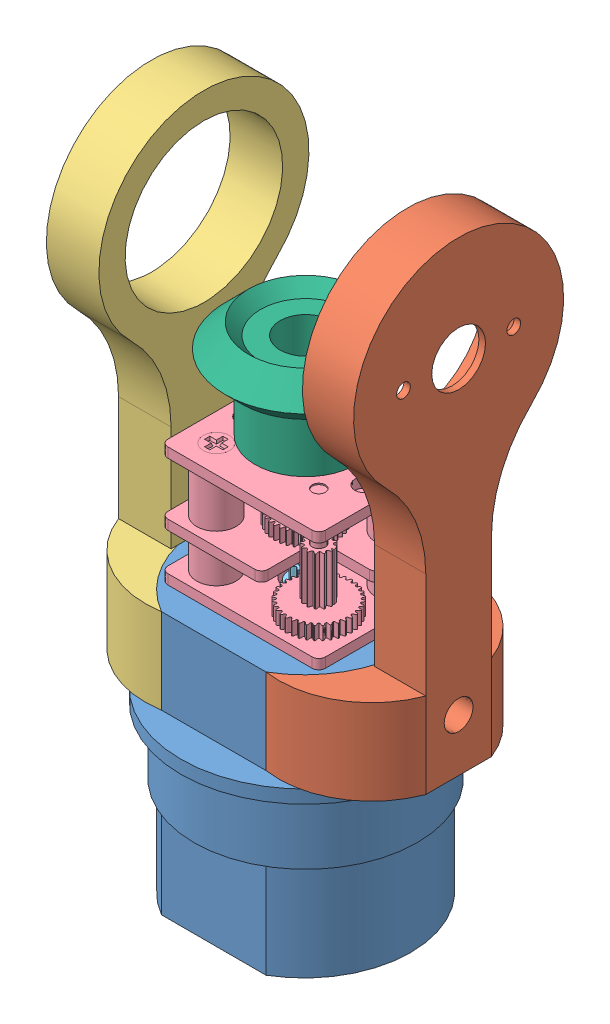
SolidWorks assembly thumb motor module, configuration Default. Lengths in mm.
Overall size (23.4 53 19).
7 component instances, 6 part files, 14 mates.
Components (placement in the parent):
- motor mount v2 thumb-1: motor mount v2 thumb [Default] at origin size (19 24 19)
- outer v2 thumb-1: outer v2 thumb [Default] at (11.65 41 0) x (0 0 1) z (-1 0 0) size (16 35.5 7.67)
- outer gearside v2 thumb-1: outer gearside v2 thumb [Default] at (-11.75 41 0) x (0 0 -1) z (0 -1 0) size (16 7.77 35.5)
- MicroGearMotor v3 Higher Detail Gears No Lead Screw-1: MicroGearMotor v3 Higher Detail Gears No Lead Screw [Default] at (0 20 0) size (12 26.96 10)
  - GearboxScaffolding-1: GearboxScaffolding [Default] at origin size (12 11.35 10)
  - DC Motor-1: DC Motor [Default] at origin size (12 18.75 10)
- rapid 50-8929-1: rapid 50-8929 [Default] at (0 30.11 0) x (0.99917 0 -0.040738) z (0.040738 0 0.99917) size (12.2 7.5 12.2)
Mates (geometry in assembly coordinates):
- Coincident1: coincident aligned: plane of motor mount v2 thumb-1 through (0 0 0) normal (0 1 0); plane of assembly through (0 0 0) normal (0 1 0)
- Coincident2: coincident aligned: plane of motor mount v2 thumb-1 through (0 0 0) normal (1 0 0); plane of assembly through (0 0 0) normal (1 0 0)
- Coincident3: coincident aligned: plane of motor mount v2 thumb-1 through (0 0 0) normal (0 0 1); plane of assembly through (0 0 0) normal (0 0 1)
- Concentric1: concentric aligned: cylinder of motor mount v2 thumb-1 through (-9.5 17.5 0) axis (1 0 0) radius 0.8; cylinder of outer v2 thumb-1 through (7.75 17.5 0) axis (1 0 0) radius 1.1
- Coincident4: coincident anti-aligned: plane of motor mount v2 thumb-1 through (0 13.5 0) normal (0 1 0); plane of outer v2 thumb-1 through (7.75 13.5 -2.5) normal (0 -1 0)
- Coincident5: coincident anti-aligned: plane of motor mount v2 thumb-1 through (7.75 9.4965 1.9978) normal (1 0 0); plane of outer v2 thumb-1 through (7.75 28.0482 12.5) normal (-1 0 0)
- Concentric2: concentric anti-aligned: cylinder of motor mount v2 thumb-1 through (-9.5 17.5 0) axis (1 0 0) radius 0.8; cylinder of outer gearside v2 thumb-1 through (-7.75 17.5 0) axis (-1 0 0) radius 1.1
- Coincident7: coincident anti-aligned: plane of motor mount v2 thumb-1 through (-7.75 9.4965 1.9978) normal (-1 0 0); plane of outer gearside v2 thumb-1 through (-7.75 28.0482 -12.5) normal (1 0 0)
- Coincident8: coincident anti-aligned: plane of motor mount v2 thumb-1 through (0 13.5 0) normal (0 1 0); plane of outer gearside v2 thumb-1 through (-7.75 13.5 2.5) normal (0 -1 0)
- Concentric3: concentric anti-aligned: cylinder of motor mount v2 thumb-1 through (0 12.5 0) axis (0 -1 0) radius 8.5; cylinder of MicroGearMotor v3 Higher Detail Gears No Lead Screw-1/GearboxScaffolding-1 through (0 29.11 0) axis (0 1 0) radius 1.7
- Parallel2: parallel aligned: plane of motor mount v2 thumb-1 through (0 20 7) normal (0 0 1); plane of MicroGearMotor v3 Higher Detail Gears No Lead Screw-1/DC Motor-1 through (3.3166 20 5) normal (0 0 1)
- Coincident10: coincident anti-aligned: plane of motor mount v2 thumb-1 through (0 20 0) normal (0 1 0); plane of MicroGearMotor v3 Higher Detail Gears No Lead Screw-1/GearboxScaffolding-1 through (0 20 0) normal (0 -1 0)
- Concentric4: concentric anti-aligned: cylinder of MicroGearMotor v3 Higher Detail Gears No Lead Screw-1/GearboxScaffolding-1 through (0 29.11 0) axis (0 1 0) radius 1.7; cylinder of rapid 50-8929-1 through (0 30.11 0) axis (0 -1 0) radius 3.85
- Coincident11: coincident anti-aligned: plane of MicroGearMotor v3 Higher Detail Gears No Lead Screw-1/GearboxScaffolding-1 through (0 30.11 0) normal (0 1 0); plane of rapid 50-8929-1 through (3.8468 30.11 -0.1568) normal (0 -1 0)
